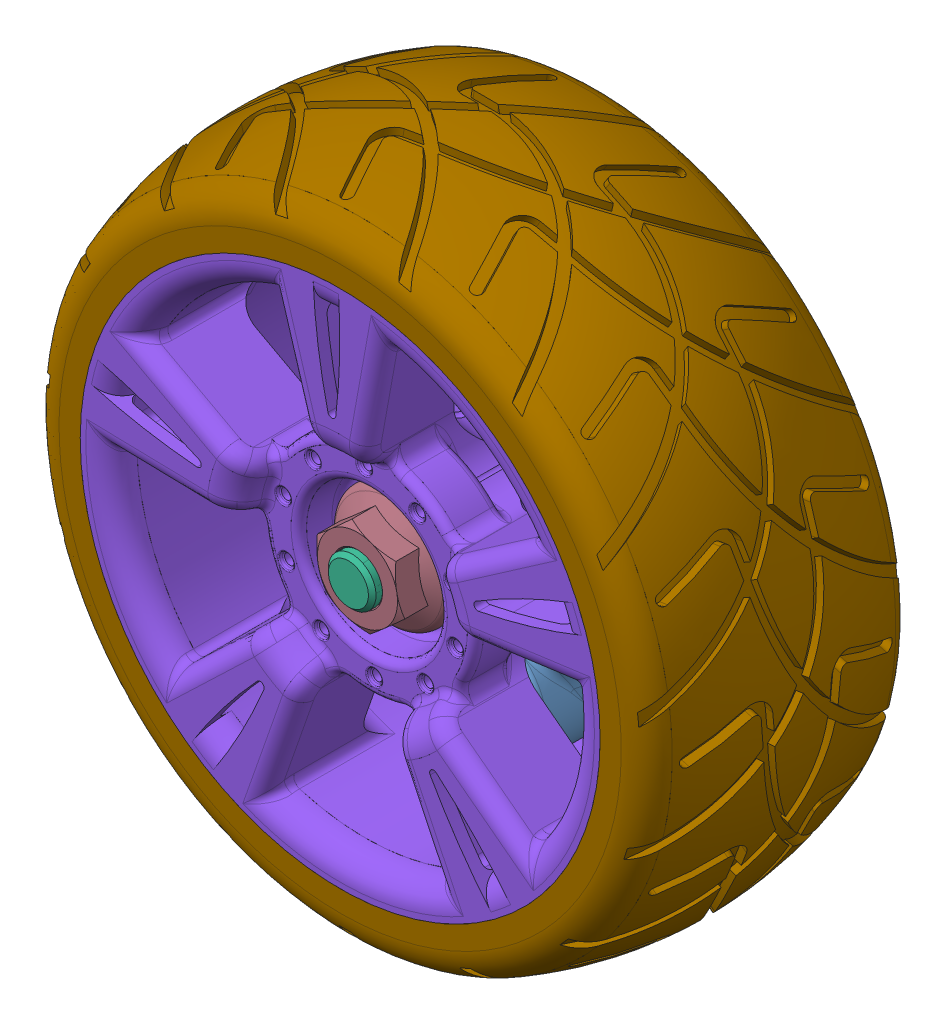
SolidWorks assembly Front hub carrier R assem, configuration Default. Lengths in mm.
Overall size (80.69 80.69 35.5).
17 component instances, 13 part files, 24 mates.
Components (placement in the parent):
- Front hub carrier R-1: Front hub carrier R [Default] at origin size (46.22 44.77 21.73)
- Pillow Ball Retainer-1: Pillow Ball Retainer [Default] at (0 16.0337 -10.9537) x (-1 0 0) z (0 0 -1) size (9.02 9.02 5.71)
- Pillow Ball Retainer-2: Pillow Ball Retainer [Default] at (0 -16.0337 -10.9537) x (-1 0 0) z (0 0 -1) size (9.02 9.02 5.71)
- Pillow Ball Bushing-1: Pillow Ball Bushing [Default] at (0 16.0337 -21.4312) x (-1 0 0) z (0 1 0) size (8.26 2.64 8.26)
- Pillow Ball Bushing-2: Pillow Ball Bushing [Default] at (0 -16.0337 -21.4312) x (-1 0 0) z (0 1 0) size (8.26 2.64 8.26)
- Rear Hub Bearing-1: Rear Hub Bearing [Default] at (0 0 -10.3187) x (0.990955 0.134195 0) z (0 0 1) size (12.7 12.7 3.17)
- front hub bearing-1: front hub bearing [Default] at (0 0 -19.8438) x (1 0 0) z (0 -1 0) size (19.05 3.17 19.05)
- front axle-1: front axle [Default] at (0 0 -16.2877) x (0.964869 0.26273 0) z (0 0 -1) size (14.29 14.71 32.13)
- 0.1875 Ball stud 0.375-1: 0.1875 Ball stud 0.375 [Default] at (-30.2632 -4.822 -25.2413) x (-0.651089 -0.174459 -0.73868) z (-0.258819 0.965926 0) size (5.5 4.76 15.1)
- Wheel R assem-1: Wheel R assem [Default] at (0 0 -20.1612) x (-0.966967 0.254903 0) z (0.254903 0.966967 0) size (66.04 26.78 66.04)
  - Wheel-1: Wheel [Default] at origin size (51.94 26.78 51.94)
  - Tire-1: Tire [Default] at (0 13.2715 0) x (0 1 0) z (0 0 1) size (26.54 66.04 66.04)
- Rear hex hub assem-1: Rear hex hub assem [Default] at (0 0 -5.8102) x (0.966967 -0.254903 0) z (0 0 -1) size (13.93 12.36 5.46)
  - Hex Drive-1: Hex Drive [Default] at origin size (13.93 12.06 5.46)
  - Hex axle pin-1: Hex axle pin [Default] x (-0.276481 0.159627 -0.94767) z (0.5 0.866025 0) size (2.38 2.38 9.53)
  - Hex retaining O-Ring-1: Hex retaining O-Ring [Default] x (1 0 0) z (0 1 0) size (12.36 1.59 12.36)
- ANSI B18.2.4.4M - M5 x 0-1: ANSI B18.2.4.4M - M5 x 0 [Default] at (0 0 -0.3493) x (0 0 1) z (-0.981021 -0.193902 0) size (5 11.8 11.8)
Mates (geometry in assembly coordinates):
- Coincident1: coincident anti-aligned: plane of Pillow Ball Retainer-1 through (0 16.0337 -16.6687) normal (0 0 -1); plane of Pillow Ball Bushing-1 through (0 16.0337 -16.6687) normal (0 0 1)
- Concentric1: concentric anti-aligned: cylinder of Pillow Ball Retainer-1 through (0 16.0337 -16.0337) axis (0 0 1) radius 4.5085; cylinder of Pillow Ball Bushing-1 through (0 16.0337 -66.8937) axis (0 0 -1) radius 4.1275
- Coincident2: coincident anti-aligned: plane of Pillow Ball Retainer-2 through (0 -16.0337 -16.6687) normal (0 0 -1); plane of Pillow Ball Bushing-2 through (0 -16.0337 -16.6687) normal (0 0 1)
- Concentric2: concentric anti-aligned: cylinder of Pillow Ball Retainer-2 through (0 -16.0337 -16.0337) axis (0 0 1) radius 4.5085; cylinder of Pillow Ball Bushing-2 through (0 -16.0337 -66.8937) axis (0 0 -1) radius 4.1275
- Concentric3: concentric aligned: cylinder of Front hub carrier R-1 through (0 16.0337 -21.4312) axis (0 0 1) radius 6.35; cylinder of Pillow Ball Retainer-1 through (0 16.0337 -16.0337) axis (0 0 1) radius 4.5085
- Concentric4: concentric: sphere of Front hub carrier R-1; sphere of Pillow Ball Bushing-1
- Concentric5: concentric aligned: cylinder of Front hub carrier R-1 through (0 -16.0337 -21.4312) axis (0 0 1) radius 6.35; cylinder of Pillow Ball Retainer-2 through (0 -16.0337 -16.0337) axis (0 0 1) radius 4.5085
- Concentric6: concentric: sphere of Front hub carrier R-1; sphere of Pillow Ball Bushing-2
- Concentric7: concentric anti-aligned: cylinder of Front hub carrier R-1 through (0 0 -11.9062) axis (0 0 1) radius 6.35; cylinder of Rear Hub Bearing-1 through (0 0 -8.7312) axis (0 0 -1) radius 6.35
- Coincident3: coincident anti-aligned: plane of Front hub carrier R-1 through (0 0 -11.9062) normal (0 0 1); plane of Rear Hub Bearing-1 through (0 0 -11.9062) normal (0 0 -1)
- Concentric8: concentric anti-aligned: cylinder of Front hub carrier R-1 through (0 0 -27.1642) axis (0 0 1) radius 6.0325; cylinder of front hub bearing-1 through (0 0 -18.2563) axis (0 0 -1) radius 7.1437
- Coincident4: coincident anti-aligned: plane of Front hub carrier R-1 through (0 0 -18.2563) normal (0 0 -1); plane of front hub bearing-1 through (0 0 -18.2563) normal (0 0 1)
- Concentric9: concentric aligned: cylinder of Rear Hub Bearing-1 through (0 0 -8.7312) axis (0 0 -1) radius 2.3813; cylinder of front axle-1 through (0 0 5.0482) axis (0 0 -1) radius 2.3813
- Coincident5: coincident aligned: plane of front hub bearing-1 through (0 0 -21.4312) normal (0 0 -1); circle of front axle-1
- Concentric10: concentric aligned: cylinder of Front hub carrier R-1 through (-30.2632 -4.822 -25.2413) axis (-0.258819 0.965926 0) radius 1.1303; cylinder of 0.1875 Ball stud 0.375-1 through (-27.7979 -14.0224 -25.2413) axis (-0.258819 0.965926 0) radius 1.4224
- Coincident6: coincident anti-aligned: plane of Front hub carrier R-1 through (-30.2632 -4.822 -25.2413) normal (-0.258819 0.965926 0); plane of 0.1875 Ball stud 0.375-1 through (-30.2632 -4.822 -25.2413) normal (0.258819 -0.965926 0)
- Coincident9: coincident anti-aligned: plane of Rear Hub Bearing-1 through (0 0 -8.7312) normal (0 0 1); plane of Rear hex hub assem-1/Hex Drive-1 through (0 0 -8.7312) normal (0 0 -1)
- Parallel2: parallel anti-aligned: cylinder of front axle-1 through (-1.9324 7.0967 -6.331) axis (0.26273 -0.964869 0) radius 1.1938; cylinder of Rear hex hub assem-1/Hex axle pin-1 through (1.2513 -4.5952 -5.8102) axis (-0.26273 0.964869 0) radius 1.1906
- Concentric14: concentric anti-aligned: cylinder of front axle-1 through (0 0 5.0482) axis (0 0 -1) radius 2.3813; cylinder of Rear hex hub assem-1/Hex Drive-1 through (0 0 -8.7312) axis (0 0 1) radius 2.3813
- Concentric15: concentric anti-aligned: cylinder of front axle-1 through (0 0 5.0482) axis (0 0 -1) radius 2.3813; cylinder of Wheel R assem-1/Wheel-1 through (0 0 -20.1612) axis (0 0 1) radius 2.3813
- Coincident10: coincident anti-aligned: plane of Wheel R assem-1/Wheel-1 through (-1.8301 6.721 -3.2703) normal (-0.254903 -0.966967 0); plane of Rear hex hub assem-1/Hex Drive-1 through (-1.8301 6.721 -8.3503) normal (0.254903 0.966967 0)
- Coincident11: coincident anti-aligned: plane of Wheel R assem-1/Wheel-1 through (0 0 -3.2703) normal (0 0 -1); plane of Rear hex hub assem-1/Hex Drive-1 through (0 0 -3.2703) normal (0 0 1)
- Concentric16: concentric aligned: cylinder of front axle-1 through (0 0 5.0482) axis (0 0 -1) radius 2.3813; cylinder of ANSI B18.2.4.4M - M5 x 0-1 through (0 0 4.2177) axis (0 0 -1) radius 2.067
- Coincident12: coincident anti-aligned: plane of Wheel R assem-1/Wheel-1 through (0 0 -0.3493) normal (0 0 1); plane of ANSI B18.2.4.4M - M5 x 0-1 through (5.8723 -3.934 -0.3493) normal (0 0 -1)
